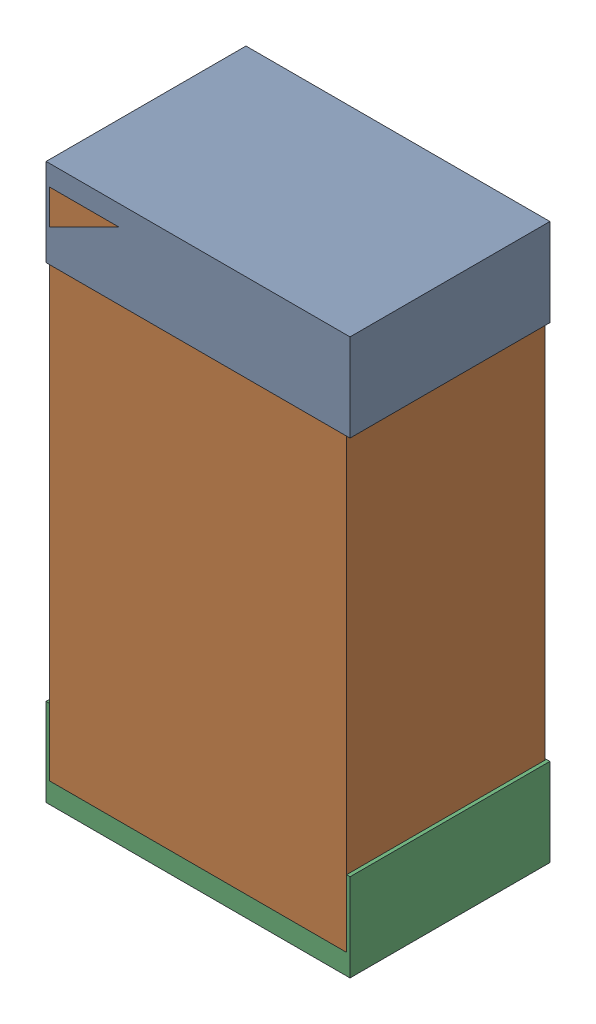
SolidWorks assembly R54Kanaloa_v2.0.0_Motor, configuration Default. Lengths in mm.
Overall size (1.3 2.38 0.85).
6 component instances, 2 part files, 0 mates.
Components (placement in the parent):
- 330415056-1: 330415056 [Default] at (136.652 150.547 -1.9574) size (1.3 0.38 0.85)
  - Extruded_2-1: Extruded_2 [Default] at origin size (1.3 0.38 0.85)
- 334787376-1: 334787376 [Default] at (136.652 149.547 -1.9524) size (1.27 2.2 0.85)
  - Extruded_16-1: Extruded_16 [Default] at origin size (1.27 2.2 0.85)
- 330415056-2: 330415056 [Default] at (136.652 148.547 -1.9574) size (1.3 0.38 0.85)
  - Extruded_2-1: Extruded_2 [Default] at origin size (1.3 0.38 0.85)
